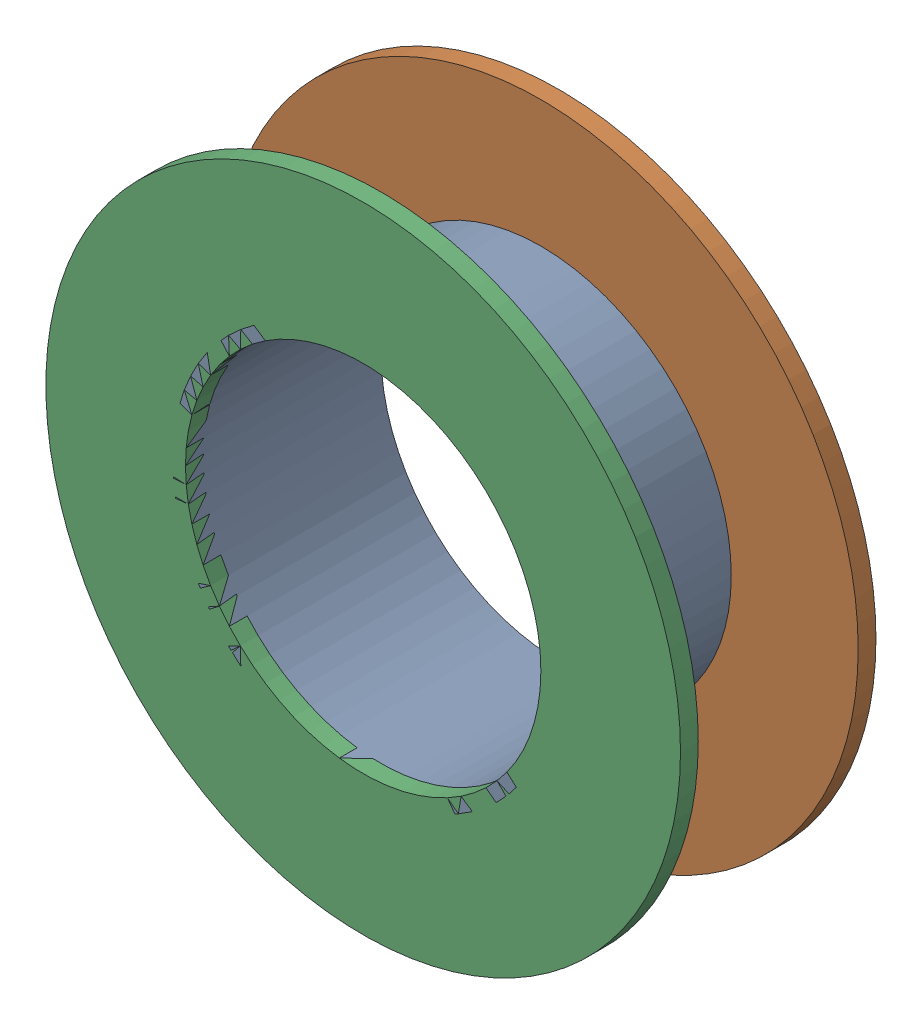
SolidWorks assembly Via (23.4mm,46.4mm) from Top Layer to Bottom Layer, configuration Predeterminado. Lengths in mm.
Overall size (1.27 1.27 0.39).
6 component instances, 2 part files, 0 mates.
Components (placement in the parent):
- Via Hole-1: Via Hole [Predeterminado] at (23.4 46.4 -0.4013) size (0.76 0.76 0.39)
  - Via Hole-Part-1-1: Via Hole-Part-1 [Predeterminado] at origin size (0.76 0.76 0.39)
- Via Top Layer-1: Via Top Layer [Predeterminado] at (23.4 46.4 -0.4013) size (1.27 1.27 0.04)
  - Via Top Layer-Part-1-1: Via Top Layer-Part-1 [Predeterminado] at origin size (1.27 1.27 0.04)
- Via Top Layer-2: Via Top Layer [Predeterminado] at (23.4 46.4 -0.0457) size (1.27 1.27 0.04)
  - Via Top Layer-Part-1-1: Via Top Layer-Part-1 [Predeterminado] at origin size (1.27 1.27 0.04)
